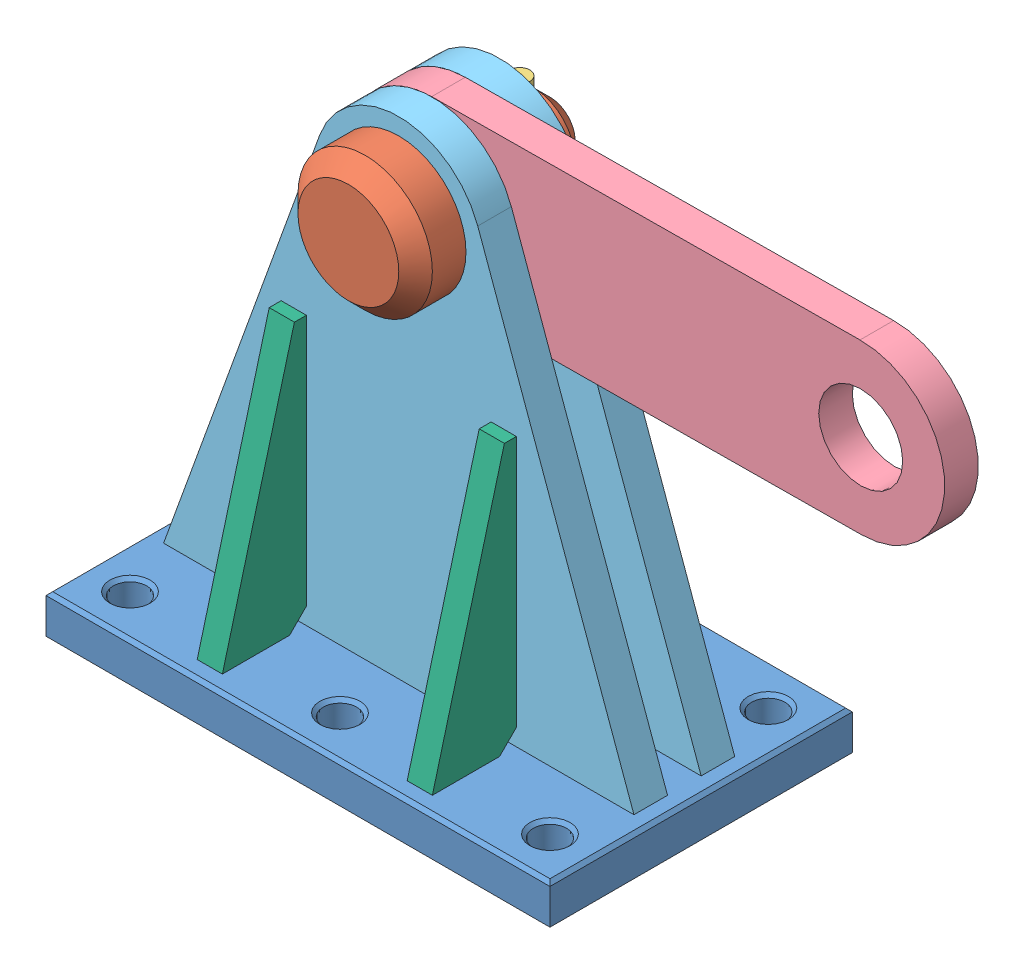
SolidWorks assembly Assem3, configuration Default. Lengths in mm.
Overall size (455.4 317.47 180).
10 component instances, 6 part files, 14 mates.
Components (placement in the parent):
- Part2-1: Part2 [Default] at (120.4317 129.1312 244.4492) size (300 25 180)
- Part3-1: Part3 [Default] at (120.4317 381.6312 294.4492) x (0 0 -1) z (0 -1 0) size (120 80 80)
- Part5-1: Part5 [Default] at (120.4317 353.1312 202.4492) x (-0.969723 0 -0.244208) z (0.244208 0 -0.969723) size (16 67 16)
- Part6-1: Part6 [Default] at (247.9275 382.6643 244.4492) x (0.008103 -0.999967 0) z (0 0 1) size (100 355 20)
- Part1-2: Part1 [Default] at (120.4317 381.6312 264.4492) size (280 290 20)
- Part1-3: Part1 [Default] at (120.4317 381.6312 224.4492) size (280 290 20)
- Part4-2: Part4 [Default] at (57.9317 221.6312 274.4492) x (0 0 -1) z (1 0 0) size (50 160 15)
- Part4-3: Part4 [Default] at (182.9317 221.6312 274.4492) x (0 0 -1) z (1 0 0) size (50 160 15)
- Part4-4: Part4 [Default] at (57.9317 221.6312 214.4492) x (0 0 1) z (-1 0 0) size (50 160 15)
- Part4-5: Part4 [Default] at (182.9317 221.6312 214.4492) x (0 0 1) z (-1 0 0) size (50 160 15)
Mates (geometry in assembly coordinates):
- Coincident1: coincident anti-aligned: plane of Part2-1 through (120.4317 141.6312 244.4492) normal (0 1 0); plane of Part1-2 through (-19.5683 141.6312 274.4492) normal (0 -1 0)
- Coincident2: coincident aligned: plane of Part2-1 through (120.4317 129.1312 244.4492) normal (1 0 0); plane of Part1-2 through (120.4317 381.6312 264.4492) normal (1 0 0)
- Distance2: distance = 10 mm anti-aligned: plane of Part2-1 through (120.4317 129.1312 244.4492) normal (0 0 1); plane of Part1-2 through (120.4317 381.6312 254.4492) normal (0 0 -1)
- Coincident5: coincident anti-aligned: plane of Part2-1 through (120.4317 141.6312 244.4492) normal (0 1 0); plane of Part4-2 through (65.4317 141.6312 284.4492) normal (0 -1 0)
- Distance4: distance = 55 mm aligned: plane of Part2-1 through (120.4317 129.1312 244.4492) normal (1 0 0); plane of Part4-2 through (65.4317 221.6312 274.4492) normal (1 0 0)
- Coincident7: coincident aligned: cylinder of Part3-1 through (120.4317 381.6312 304.4492) axis (0 0 1) radius 25; circle of Part1-2
- Coincident8: coincident anti-aligned: plane of Part3-1 through (145.4317 381.6312 274.4492) normal (0 0 -1); plane of Part1-2 through (120.4317 381.6312 274.4492) normal (0 0 1)
- Concentric1: concentric anti-aligned: cylinder of Part3-1 through (120.4317 381.6312 304.4492) axis (0 0 1) radius 25; cylinder of Part6-1 through (120.4317 381.6312 254.4492) axis (0 0 -1) radius 25
- Coincident10: coincident anti-aligned: plane of Part1-3 through (120.4317 381.6312 214.4492) normal (0 0 -1); plane of Part4-4 through (50.4317 301.6312 214.4492) normal (0 0 1)
- Coincident11: coincident anti-aligned: plane of Part6-1 through (375.4233 383.6974 234.4492) normal (0 0 -1); plane of Part1-3 through (120.4317 381.6312 234.4492) normal (0 0 1)
- Concentric2: concentric aligned: cylinder of Part3-1 through (120.4317 436.6312 202.4492) axis (0 -1 0) radius 6; cylinder of Part5-1 through (120.4317 416.6312 202.4492) axis (0 -1 0) radius 6
- Tangent1: tangent anti-aligned: cylinder of Part3-1 through (120.4317 381.6312 304.4492) axis (0 0 1) radius 25; plane of Part5-1 through (120.4317 356.6312 202.4492) normal (0 1 0)
- Parallel2: parallel anti-aligned: plane of Part5-1 through (120.4317 349.6312 202.4492) normal (0 -1 0); plane of Part4-5 through (175.4317 301.6312 214.4492) normal (0 1 0)
- LimitAngle1: limit planar angle = 3.13349 rad aligned: plane of Part6-1 through (375.8284 333.699 254.4492) normal (0.008103 -0.999967 0); plane of Part2-1 through (120.4317 141.6312 244.4492) normal (0 1 0)
